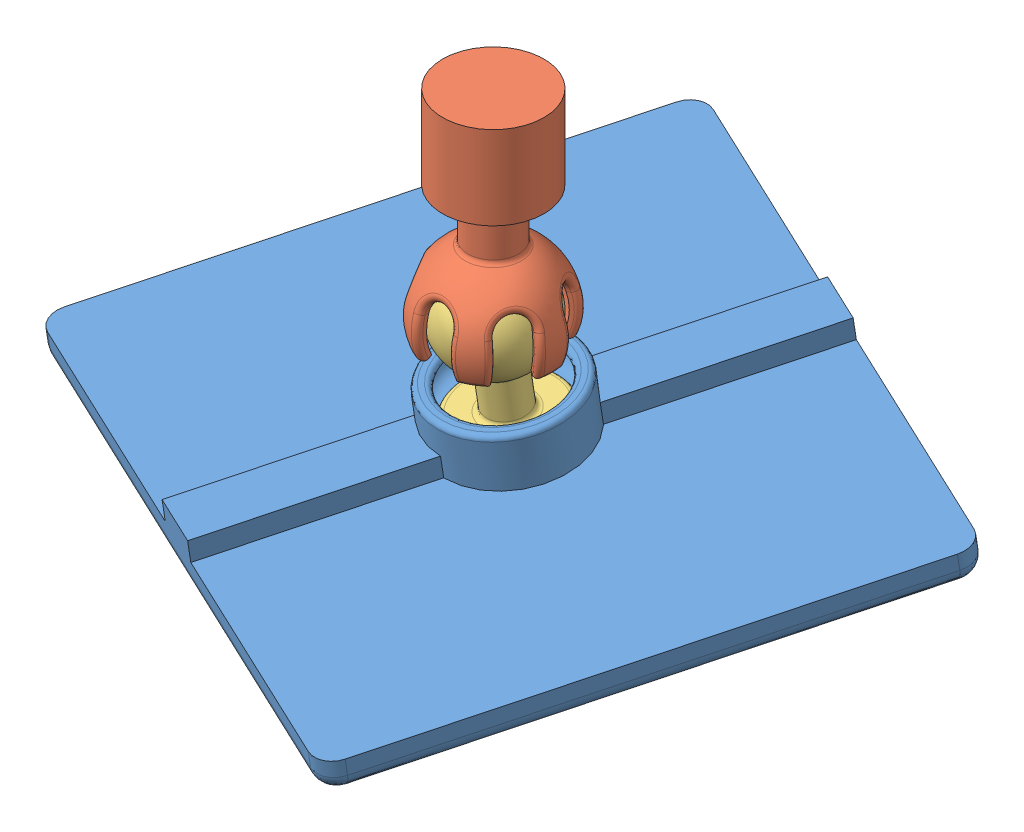
SolidWorks assembly Wang-SolarPowerSystem-New, configuration Default. Lengths in mm.
Overall size (70.79 37.37 68.68).
3 component instances, 3 part files, 4 mates.
Components (placement in the parent):
- Solar Panel-1: Solar Panel [Default] at (10.4392 1.468 -24.0892) x (-0.410009 -0.134343 0.902133) z (0.91192 -0.041749 0.40824) size (50 8 55)
- BallCasterJoyStick-Socket-2: BallCasterJoyStick-Socket [Default] at origin size (12.6 21.53 11.89)
- BallCasterJoyStick-Ball-2: BallCasterJoyStick-Ball [Default] at (0.1546 0.0895 -1.2566) x (-0.05017 -0.140325 0.988834) z (-0.998593 -0.009984 -0.052082) size (10 16 10)
Mates (geometry in assembly coordinates):
- Concentric2: concentric: sphere of BallCasterJoyStick-Socket-2; sphere of BallCasterJoyStick-Ball-2
- LimitDistance3: limit distance = 21.6733 mm: point of BallCasterJoyStick-Ball-2; plane of BallCasterJoyStick-Socket-2 through (-5 19.7827 0) normal (0 -1 0)
- Coincident1: coincident anti-aligned: plane of Solar Panel-1 through (35.517 0.3199 -12.8626) normal (-0.017181 0.990055 0.139627); plane of BallCasterJoyStick-Ball-2 through (0.189 -1.8906 -1.5359) normal (0.017181 -0.990055 -0.139627)
- Concentric4: concentric anti-aligned: circle of Solar Panel-1; circle of BallCasterJoyStick-Ball-2
